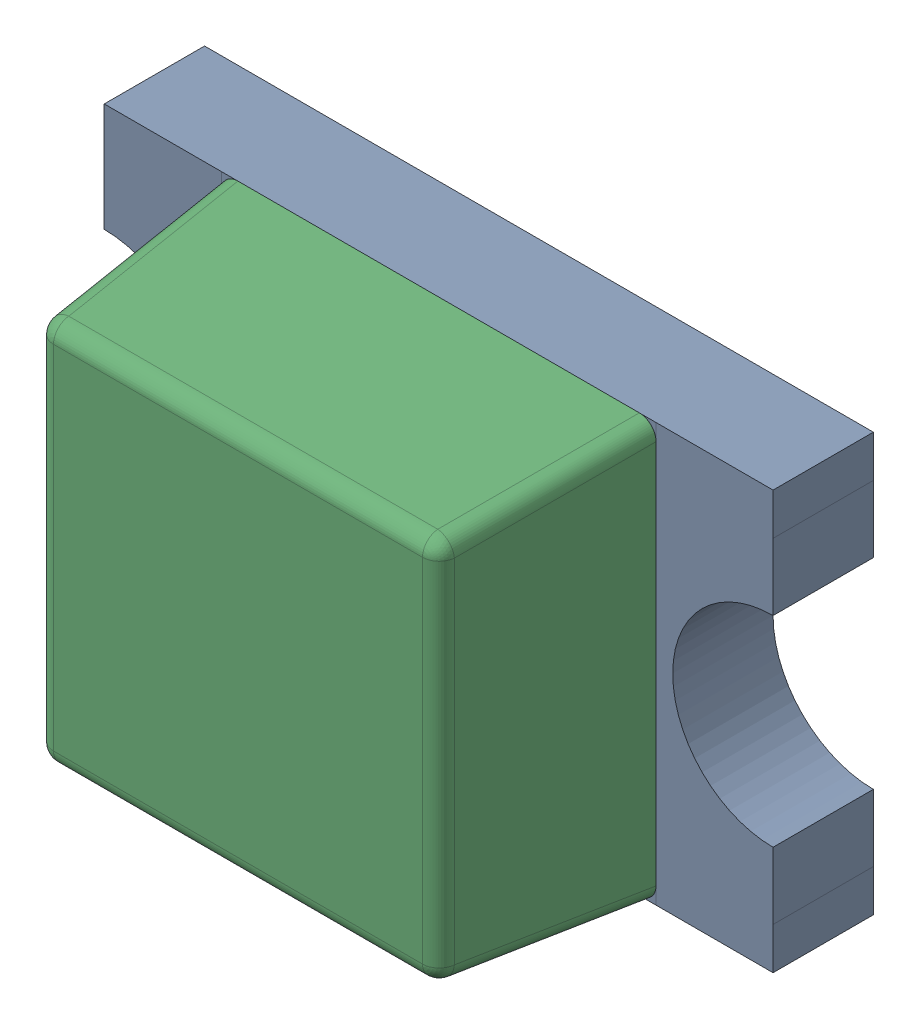
SolidWorks assembly D4_1.step, configuration Default. Lengths in mm.
Overall size (2 1.25 0.9).
2 component instances, 2 part files, 0 mates.
Components (placement in the parent):
- LED 0805 Base RED_1.step-11: LED 0805 Base RED_1.step [Default] at (506.9841 335.28 0) x (1 0 0) z (0 -1 0) size (2 0.4 1.25)
- LED 0805 Lens RED_1.step-11: LED 0805 Lens RED_1.step [Default] at (506.9841 335.28 0) x (1 0 0) z (0 -1 0) size (1.3 0.6 1.25)
